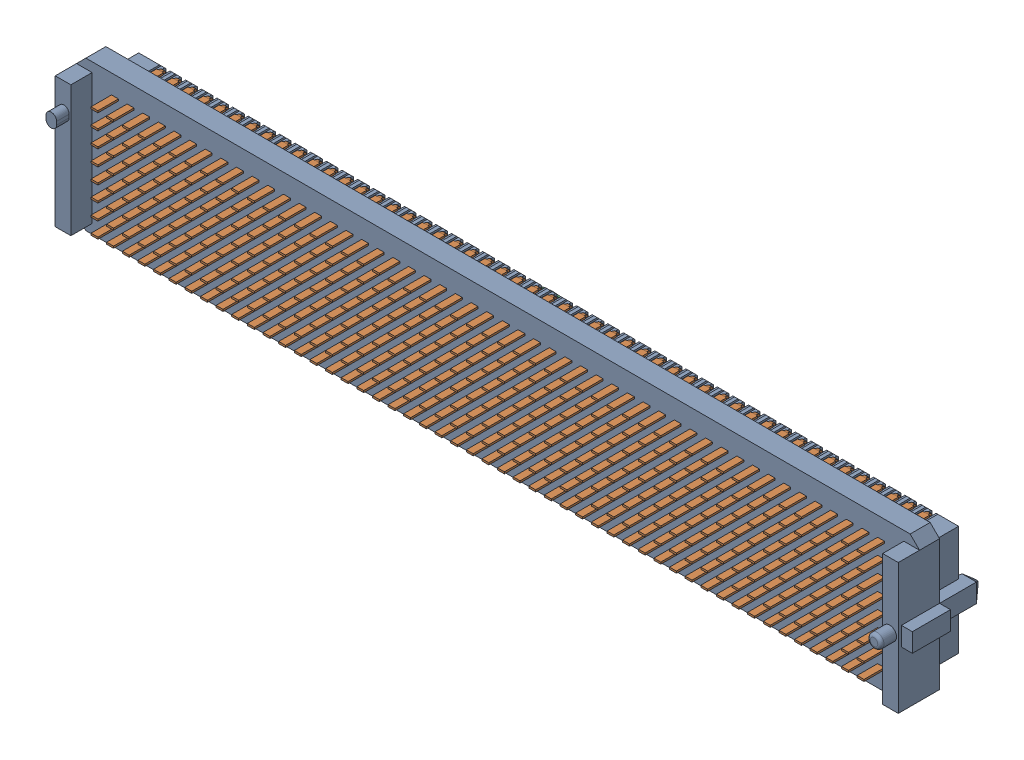
SolidWorks assembly P1, configuration Default. Lengths in mm.
Overall size (69.37 12.14 8.38).
5 component instances, 4 part files, 0 mates.
Components (placement in the parent):
- SEAM-50-03.5-S-08-2-A-K-TR-1: SEAM-50-03.5-S-08-2-A-K-TR [Default] at (43.4999 7.4255 -4.9661) x (1 0 0) z (0 1 0) size (69.37 8.38 12.14)
  - _SEAM-50-03.5-L-08-1-A-K-TR_body-1: _SEAM-50-03.5-L-08-1-A-K-TR_body [Default] at origin size (69.37 8.38 12.14)
  - _SEAM-50-03.5-L-08-1-A-K-TR_conn-1: _SEAM-50-03.5-L-08-1-A-K-TR_conn [Default] at origin size (67.97 5.75 11.63)
  - _SEAM_K_Pad_08-1: _SEAM_K_Pad_08 [Default] at (0 2.7432 0) size (8.26 0.13 8.26)
  - _SEAM_Triangle-1: _SEAM_Triangle [Default] at (32.2834 1.3462 -4.2164) x (-1 0 0) z (0 0 -1) size (1.02 1.27 0.13)
